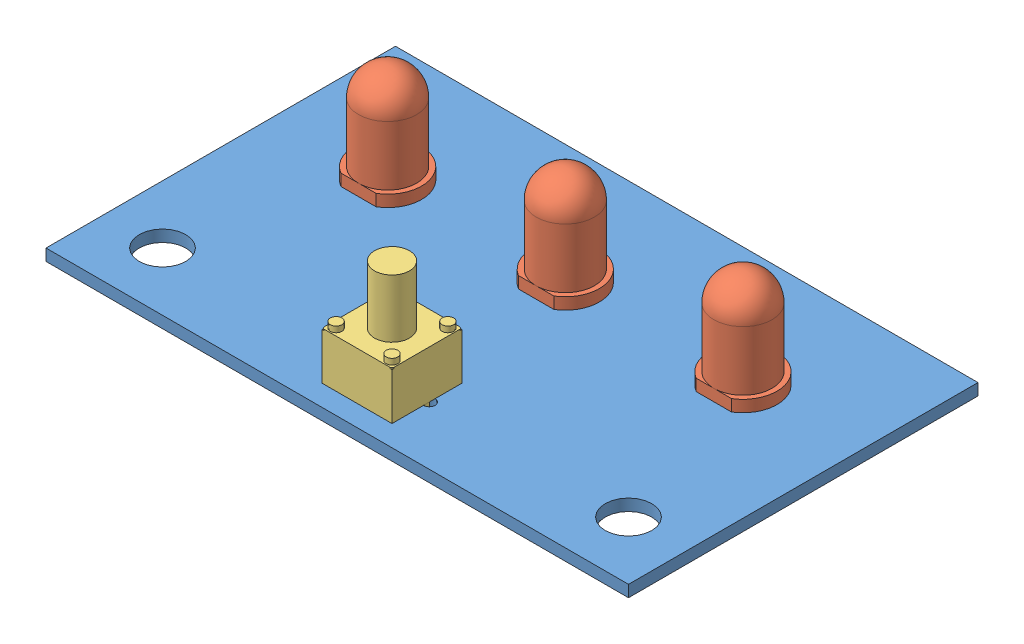
SolidWorks assembly PCB montada, configuration Default. Lengths in mm.
Overall size (50 14.6 30).
5 component instances, 3 part files, 6 mates.
Components (placement in the parent):
- Placa pcb universal-1: Placa pcb universal [Default] at (-62.7024 9.8725 30.3481) size (50 1 30)
- led-1: led [Default] at (-53.1087 11.8725 10.6181) x (1 0 0) z (0 1 0) size (5.85 5.42 13.6)
- led-2: led [Default] at (-37.8587 11.8725 10.6181) x (1 0 0) z (0 1 0) size (5.85 5.42 13.6)
- led-3: led [Default] at (-22.6087 11.8725 10.6181) x (1 0 0) z (0 1 0) size (5.85 5.42 13.6)
- Botao push pull-1: Botao push pull [Default] at (-40.8024 10.8725 28.5481) size (6 14.6 6)
Mates (geometry in assembly coordinates):
- Coincident1: coincident anti-aligned: plane of Placa pcb universal-1 through (-62.7024 10.8725 30.3481) normal (0 1 0); plane of led-1 through (-53.1087 10.8725 10.6181) normal (0 -1 0)
- Concentric1: concentric aligned: circle of Placa pcb universal-1; line of led-1 through (-52.9524 5.8725 9.0981) axis (0 1 0)
- Coincident3: coincident aligned: plane of led-1 through (-51.5903 6.8725 13.1181) normal (0 0 1); plane of led-2 through (-36.3403 6.8725 13.1181) normal (0 0 1)
- Concentric2: concentric aligned: circle of Placa pcb universal-1; line of Botao push pull-1 through (-40.6024 5.3725 25.3481) axis (0 1 0)
- Coincident4: coincident anti-aligned: plane of Placa pcb universal-1 through (-62.7024 10.8725 30.3481) normal (0 1 0); plane of Botao push pull-1 through (-40.8024 10.8725 28.5481) normal (0 -1 0)
- Parallel2: parallel anti-aligned: plane of led-2 through (-36.3403 6.8725 13.1181) normal (0 0 1); plane of Botao push pull-1 through (-40.8024 14.8725 22.5481) normal (0 0 -1)
